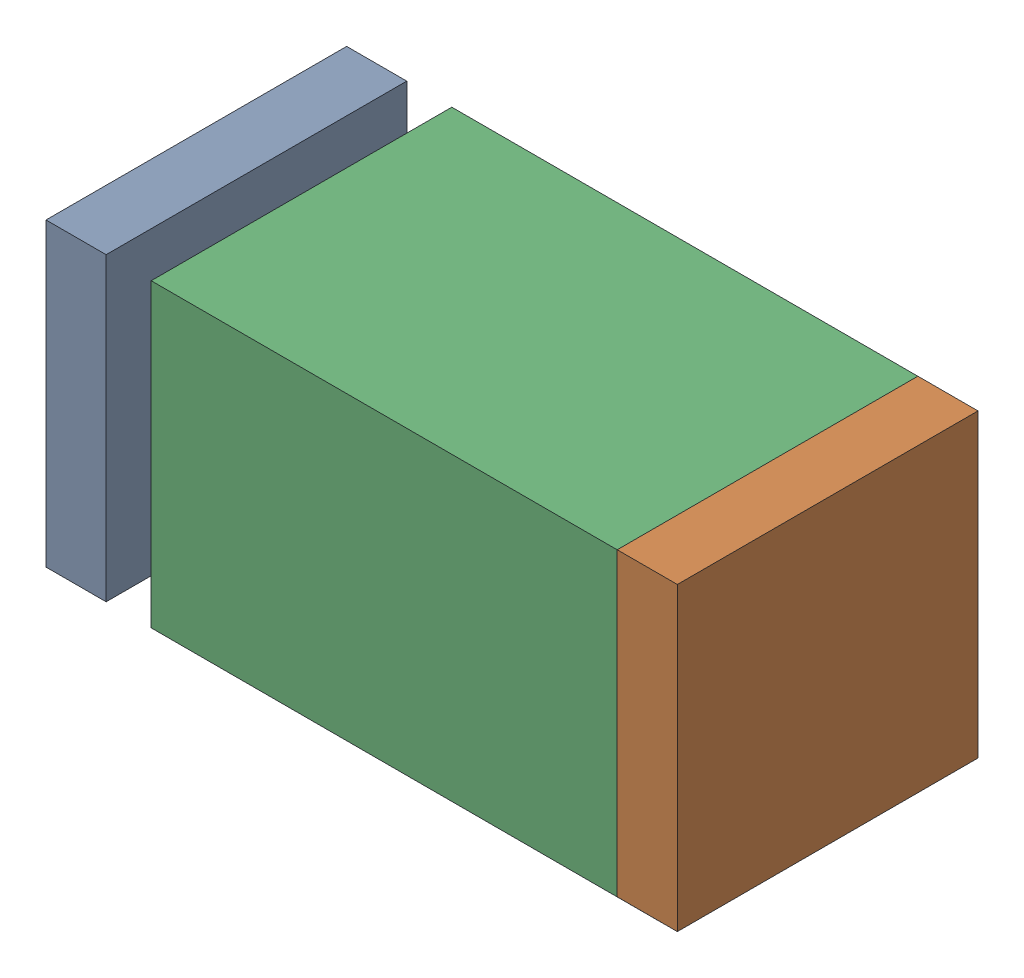
SolidWorks assembly C28, configuration Default. Lengths in mm.
Overall size (1.05 0.5 0.5).
6 component instances, 2 part files, 0 mates.
Components (placement in the parent):
- 810156080-1: 810156080 [Default] at (130.5 26.85 0) size (0.1 0.5 0.5)
  - Extruded_5-1: Extruded_5 [Default] at origin size (0.1 0.5 0.5)
- 810156080-2: 810156080 [Default] at (131.45 26.85 0) size (0.1 0.5 0.5)
  - Extruded_5-1: Extruded_5 [Default] at origin size (0.1 0.5 0.5)
- 810156208-1: 810156208 [Default] at (131.0499 26.8499 0) size (0.85 0.5 0.5)
  - Extruded_17-1: Extruded_17 [Default] at origin size (0.85 0.5 0.5)
